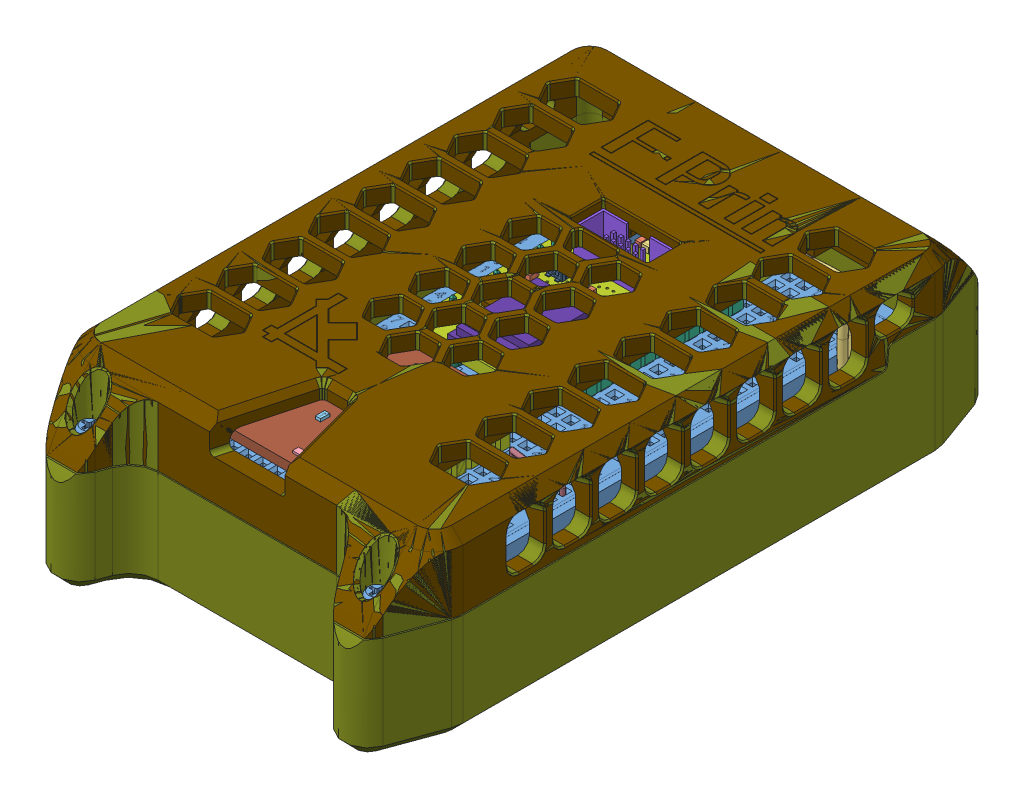
SolidWorks assembly FPR12096, configuration Screw Boss. Lengths in mm.
Overall size (66.81 31.19 108.52).
130 component instances, 41 part files, 64 mates.
Components (placement in the parent):
- HalfBreadboard.step-1: HalfBreadboard.step [Default] at (41.91 0 0)
- Thermo_28_click_v101.step-1: Thermo_28_click_v101.step [Default] at (11.403 8.3902 13.97) x (-1 0 0) z (0 1 0) size (25.78 28.57 12.19)
  - R5.step-1: R5.step [Default] at origin size (1 0.5 0.35)
    - User_Library-R_0402.step-1: User_Library-R_0402.step [Default] at (7.874 2.6926 0) x (1 0 0) z (0 0 1) size (1 0.5 0.35)
  - JP1.step-1: JP1.step [Default] at origin size (1.25 2 0.5)
    - User_Library-R_0805.step-1: User_Library-R_0805.step [Default] at (11.4299 6.5947 0) x (0 1 0) z (0 0 1) size (2 1.25 0.5)
  - U1.step-1: U1.step [Default] at origin size (1.52 1.04 0.61)
    - AS6221-AWLT-S_AMS.step-1: AS6221-AWLT-S_AMS.step [Default] at (11.4555 22.8569 0) x (1 0 0) z (0 0 1) size (1.52 1.04 0.61)
  - R3.step-1: R3.step [Default] at origin size (0.9 1.6 0.5)
    - User_Library-R_0603.step-1: User_Library-R_0603.step [Default] at (15.1129 15.2401 0) x (0 1 0) z (0 0 1) size (1.6 0.9 0.5)
  - R2.step-1: R2.step [Default] at origin size (0.9 1.6 0.5)
    - User_Library-R_0603.step-1: User_Library-R_0603.step [Default] at (11.4299 15.2147 0) x (0 1 0) z (0 0 1) size (1.6 0.9 0.5)
  - R4.step-1: R4.step [Default] at origin size (0.9 1.6 0.5)
    - User_Library-R_0603.step-1: User_Library-R_0603.step [Default] at (7.7977 15.2401 0) x (0 1 0) z (0 0 1) size (1.6 0.9 0.5)
  - C1.step-1: C1.step [Default] at origin size (0.5 1 0.5)
    - User_Library-SMD_CAPACITOR0402.step-1: User_Library-SMD_CAPACITOR0402.step [Default] at (9.9061 22.7838 0.24) x (0 -1 0) z (0 0 1) size (1 0.5 0.5)
  - MBD1.step-1: MBD1.step [Default] at origin size (25.78 20.32 12.19)
    - Header_1x8.step-1: Header_1x8.step [Default] at (-74.8548 -67.056 0) size (2.92 20.32 12.19)
      - PCB.step-1: PCB.step [Default] at origin size (2.92 20.32 12.19)
        - Free-Models.step-1: Free-Models.step [Default] at origin size (2.92 20.32 12.19)
          - 1240637040.step-1: 1240637040.step [Default] at (97.7778 84.836 -1.6002) x (0 -1 0) z (1 0 0) size (12.7 12.19 2.92)
            - User_Library-PinHeaderX5-1_PinHeaderX5_Body_1.step-1: User_Library-PinHeaderX5-1_PinHeaderX5_Body_1.step [Default] at origin size (12.7 2.54 2.92)
            - User_Library-PinHeaderX5-1_PinHeaderX5_Pins_1.step-1: User_Library-PinHeaderX5-1_PinHeaderX5_Pins_1.step [Default] at origin size (10.8 12.19 0.64)
          - 1240637040.step-2: 1240637040.step [Default] at (97.7778 77.216 -1.6002) x (0 -1 0) z (1 0 0) size (12.7 12.19 2.92)
            - User_Library-PinHeaderX5-1_PinHeaderX5_Body_1.step-1: User_Library-PinHeaderX5-1_PinHeaderX5_Body_1.step [Default] at origin size (12.7 2.54 2.92)
            - User_Library-PinHeaderX5-1_PinHeaderX5_Pins_1.step-1: User_Library-PinHeaderX5-1_PinHeaderX5_Pins_1.step [Default] at origin size (10.8 12.19 0.64)
    - Header_1x8.step-2: Header_1x8.step [Default] at (-97.7148 -67.056 0) size (2.92 20.32 12.19)
      - PCB.step-1: PCB.step [Default] at origin size (2.92 20.32 12.19)
        - Free-Models.step-1: Free-Models.step [Default] at origin size (2.92 20.32 12.19)
          - 1240637040.step-1: 1240637040.step [Default] at (97.7778 84.836 -1.6002) x (0 -1 0) z (1 0 0) size (12.7 12.19 2.92)
            - User_Library-PinHeaderX5-1_PinHeaderX5_Body_1.step-1: User_Library-PinHeaderX5-1_PinHeaderX5_Body_1.step [Default] at origin size (12.7 2.54 2.92)
            - User_Library-PinHeaderX5-1_PinHeaderX5_Pins_1.step-1: User_Library-PinHeaderX5-1_PinHeaderX5_Pins_1.step [Default] at origin size (10.8 12.19 0.64)
          - 1240637040.step-2: 1240637040.step [Default] at (97.7778 77.216 -1.6002) x (0 -1 0) z (1 0 0) size (12.7 12.19 2.92)
            - User_Library-PinHeaderX5-1_PinHeaderX5_Body_1.step-1: User_Library-PinHeaderX5-1_PinHeaderX5_Body_1.step [Default] at origin size (12.7 2.54 2.92)
            - User_Library-PinHeaderX5-1_PinHeaderX5_Pins_1.step-1: User_Library-PinHeaderX5-1_PinHeaderX5_Pins_1.step [Default] at origin size (10.8 12.19 0.64)
  - LD1.step-1: LD1.step [Default] at origin size (2.02 1.25 1.1)
    - led_0805_green.step-1: led_0805_green.step [Default] at (13.7413 1.651 0) x (-1 0 0) z (0 0 1) size (2.02 1.25 1.1)
  - R1.step-1: R1.step [Default] at origin size (2 1.25 0.5)
    - User_Library-R_0805.step-1: User_Library-R_0805.step [Default] at (13.7414 0.0001 0) x (1 0 0) z (0 0 1) size (2 1.25 0.5)
  - C2.step-1: C2.step [Default] at origin size (1 0.5 0.5)
    - User_Library-SMD_CAPACITOR0402.step-1: User_Library-SMD_CAPACITOR0402.step [Default] at (10.4139 2.6925 0.24) x (1 0 0) z (0 0 1) size (1 0.5 0.5)
  - U2.step-1: U2.step [Default] at origin size (2.76 3 1)
    - 756579480.step-1: 756579480.step [Default] at (9.144 0.7366 0) size (2.76 3 1)
      - Extruded.step-1: Extruded.step [Default] at origin size (2.76 3 1)
  - Board.step-1: Board.step [Default] at origin size (25.4 28.57 1.59)
- VCC^FPR12096-1: VCC^FPR12096 [Default] at origin (virtual)
- GND^FPR12096-1: GND^FPR12096 [Default] at origin (virtual)
- SDA^FPR12096-1: SDA^FPR12096 [Default] at origin (virtual)
- SCL^FPR12096-1: SCL^FPR12096 [Default] at origin (virtual)
- FPR12097-1: FPR12097 [Screw Boss] at (0 -6.8 0) size (66.81 30.8 108.52)
- 95495K18-1: 95495K18 [Default] at (-20 -15.1437 -33.5) x (0.277584 0 -0.960701) z (-0.960701 0 -0.277584)
- 95495K18-2: 95495K18 [Default] at (20 -15.1437 -33.5) x (0.091561 0 -0.995799) z (-0.995799 0 -0.091561)
- 95495K18-4: 95495K18 [Default] at (20 -15.1437 33.5) x (-0.125259 0 -0.992124) z (-0.992124 0 0.125259)
- 95495K18-6: 95495K18 [Default] at (-20 -15.1437 33.5) x (-0.354354 0 -0.935112) z (-0.935112 0 0.354354)
- FPR12098-1: FPR12098 [Screw Boss] at (0 -6.8 0) size (66.81 15.35 104.67)
- 99461A916-1: 99461A916 [Default] at (-25 4.955 48.5) x (1 0 0) z (0 1 0)
- 99461A916-2: 99461A916 [Default] at (25 4.955 48.5) x (1 0 0) z (0 1 0)
- 99461A916-3: 99461A916 [Default] at (-25 7.455 -48.5) x (1 0 0) z (0 1 0)
- 99461A916-4: 99461A916 [Default] at (25 7.455 -48.5) x (1 0 0) z (0 1 0)
- 2011 2000mAh Battery.step-1: 2011 2000mAh Battery.step [Default] at (0 -13.3 5) x (1 0 0) z (0 1 0)
- BatteryCable^FPR12096-1: BatteryCable^FPR12096 [Default] at origin size (51.69 24.18 9.65) (virtual)
- PHR-2-for-Battery-Adafruit.stp-1: PHR-2-for-Battery-Adafruit.stp [Default] at (11.079 8.7636 -30.135) x (0 0 1) z (-1 0 0) size (5.8 4.5 11.15)
- 5862K141-1: 5862K141 [Default] at (0 -14.5563 -15) x (1 0 0) z (0 1 0)
- 5862K141-2: 5862K141 [Default] at (0 -14.5563 15) x (0.982082 0 -0.188455) z (0 1 0)
- nRF52840 Feather-1: nRF52840 Feather [Default] at (-10.25 7.0486 -43.18) x (0 0 1) z (0 1 0) size (51.45 22.86 16.48)
  - Pin Header 1x1 TH Pitch 2.54mm^nRF52840 Feather-1: Pin Header 1x1 TH Pitch 2.54mm^nRF52840 Feather [Default] at (6.35 1.27 0.0014) x (0 1 0) z (0 0 -1) size (2.54 2.54 12.7) (virtual)
  - Pin Header 1x1 TH Pitch 2.54mm^nRF52840 Feather-56: Pin Header 1x1 TH Pitch 2.54mm^nRF52840 Feather [Default] at (8.89 1.27 0.0014) x (0 1 0) z (0 0 -1) size (2.54 2.54 12.7) (virtual)
  - Pin Header 1x1 TH Pitch 2.54mm^nRF52840 Feather-57: Pin Header 1x1 TH Pitch 2.54mm^nRF52840 Feather [Default] at (11.43 1.27 0.0014) x (0 1 0) z (0 0 -1) size (2.54 2.54 12.7) (virtual)
  - Pin Header 1x1 TH Pitch 2.54mm^nRF52840 Feather-58: Pin Header 1x1 TH Pitch 2.54mm^nRF52840 Feather [Default] at (13.97 1.27 0.0014) x (0 1 0) z (0 0 -1) size (2.54 2.54 12.7) (virtual)
  - Pin Header 1x1 TH Pitch 2.54mm^nRF52840 Feather-59: Pin Header 1x1 TH Pitch 2.54mm^nRF52840 Feather [Default] at (16.51 1.27 0.0014) x (0 1 0) z (0 0 -1) size (2.54 2.54 12.7) (virtual)
  - Pin Header 1x1 TH Pitch 2.54mm^nRF52840 Feather-60: Pin Header 1x1 TH Pitch 2.54mm^nRF52840 Feather [Default] at (19.05 1.27 0.0014) x (0 1 0) z (0 0 -1) size (2.54 2.54 12.7) (virtual)
  - Pin Header 1x1 TH Pitch 2.54mm^nRF52840 Feather-61: Pin Header 1x1 TH Pitch 2.54mm^nRF52840 Feather [Default] at (21.59 1.27 0.0014) x (0 1 0) z (0 0 -1) size (2.54 2.54 12.7) (virtual)
  - Pin Header 1x1 TH Pitch 2.54mm^nRF52840 Feather-62: Pin Header 1x1 TH Pitch 2.54mm^nRF52840 Feather [Default] at (24.13 1.27 0.0014) x (0 1 0) z (0 0 -1) size (2.54 2.54 12.7) (virtual)
  - Pin Header 1x1 TH Pitch 2.54mm^nRF52840 Feather-63: Pin Header 1x1 TH Pitch 2.54mm^nRF52840 Feather [Default] at (26.67 1.27 0.0014) x (0 1 0) z (0 0 -1) size (2.54 2.54 12.7) (virtual)
  - Pin Header 1x1 TH Pitch 2.54mm^nRF52840 Feather-64: Pin Header 1x1 TH Pitch 2.54mm^nRF52840 Feather [Default] at (29.21 1.27 0.0014) x (0 1 0) z (0 0 -1) size (2.54 2.54 12.7) (virtual)
  - Pin Header 1x1 TH Pitch 2.54mm^nRF52840 Feather-65: Pin Header 1x1 TH Pitch 2.54mm^nRF52840 Feather [Default] at (31.75 1.27 0.0014) x (0 1 0) z (0 0 -1) size (2.54 2.54 12.7) (virtual)
  - Pin Header 1x1 TH Pitch 2.54mm^nRF52840 Feather-66: Pin Header 1x1 TH Pitch 2.54mm^nRF52840 Feather [Default] at (34.29 1.27 0.0014) x (0 1 0) z (0 0 -1) size (2.54 2.54 12.7) (virtual)
  - Pin Header 1x1 TH Pitch 2.54mm^nRF52840 Feather-67: Pin Header 1x1 TH Pitch 2.54mm^nRF52840 Feather [Default] at (36.83 1.27 0.0014) x (0 1 0) z (0 0 -1) size (2.54 2.54 12.7) (virtual)
  - Pin Header 1x1 TH Pitch 2.54mm^nRF52840 Feather-68: Pin Header 1x1 TH Pitch 2.54mm^nRF52840 Feather [Default] at (39.37 1.27 0.0014) x (0 1 0) z (0 0 -1) size (2.54 2.54 12.7) (virtual)
  - Pin Header 1x1 TH Pitch 2.54mm^nRF52840 Feather-69: Pin Header 1x1 TH Pitch 2.54mm^nRF52840 Feather [Default] at (41.91 1.27 0.0014) x (0 1 0) z (0 0 -1) size (2.54 2.54 12.7) (virtual)
  - Pin Header 1x1 TH Pitch 2.54mm^nRF52840 Feather-70: Pin Header 1x1 TH Pitch 2.54mm^nRF52840 Feather [Default] at (44.45 1.27 0.0014) x (0 1 0) z (0 0 -1) size (2.54 2.54 12.7) (virtual)
  - Pin Header 1x1 TH Pitch 2.54mm^nRF52840 Feather-71: Pin Header 1x1 TH Pitch 2.54mm^nRF52840 Feather [Default] at (44.45 21.59 0.0014) x (0 -1 0) z (0 0 -1) size (2.54 2.54 12.7) (virtual)
  - Pin Header 1x1 TH Pitch 2.54mm^nRF52840 Feather-72: Pin Header 1x1 TH Pitch 2.54mm^nRF52840 Feather [Default] at (41.91 21.59 0.0014) x (0 -1 0) z (0 0 -1) size (2.54 2.54 12.7) (virtual)
  - Pin Header 1x1 TH Pitch 2.54mm^nRF52840 Feather-73: Pin Header 1x1 TH Pitch 2.54mm^nRF52840 Feather [Default] at (39.37 21.59 0.0014) x (0 -1 0) z (0 0 -1) size (2.54 2.54 12.7) (virtual)
  - Pin Header 1x1 TH Pitch 2.54mm^nRF52840 Feather-74: Pin Header 1x1 TH Pitch 2.54mm^nRF52840 Feather [Default] at (36.83 21.59 0.0014) x (0 -1 0) z (0 0 -1) size (2.54 2.54 12.7) (virtual)
  - Pin Header 1x1 TH Pitch 2.54mm^nRF52840 Feather-75: Pin Header 1x1 TH Pitch 2.54mm^nRF52840 Feather [Default] at (34.29 21.59 0.0014) x (0 -1 0) z (0 0 -1) size (2.54 2.54 12.7) (virtual)
  - Pin Header 1x1 TH Pitch 2.54mm^nRF52840 Feather-76: Pin Header 1x1 TH Pitch 2.54mm^nRF52840 Feather [Default] at (31.75 21.59 0.0014) x (0 -1 0) z (0 0 -1) size (2.54 2.54 12.7) (virtual)
  - Pin Header 1x1 TH Pitch 2.54mm^nRF52840 Feather-77: Pin Header 1x1 TH Pitch 2.54mm^nRF52840 Feather [Default] at (29.21 21.59 0.0014) x (0 -1 0) z (0 0 -1) size (2.54 2.54 12.7) (virtual)
  - Pin Header 1x1 TH Pitch 2.54mm^nRF52840 Feather-78: Pin Header 1x1 TH Pitch 2.54mm^nRF52840 Feather [Default] at (26.67 21.59 0.0014) x (0 -1 0) z (0 0 -1) size (2.54 2.54 12.7) (virtual)
  - Pin Header 1x1 TH Pitch 2.54mm^nRF52840 Feather-79: Pin Header 1x1 TH Pitch 2.54mm^nRF52840 Feather [Default] at (24.13 21.59 0.0014) x (0 -1 0) z (0 0 -1) size (2.54 2.54 12.7) (virtual)
  - Pin Header 1x1 TH Pitch 2.54mm^nRF52840 Feather-80: Pin Header 1x1 TH Pitch 2.54mm^nRF52840 Feather [Default] at (21.59 21.59 0.0014) x (0 -1 0) z (0 0 -1) size (2.54 2.54 12.7) (virtual)
  - Pin Header 1x1 TH Pitch 2.54mm^nRF52840 Feather-81: Pin Header 1x1 TH Pitch 2.54mm^nRF52840 Feather [Default] at (19.05 21.59 0.0014) x (0 -1 0) z (0 0 -1) size (2.54 2.54 12.7) (virtual)
  - Pin Header 1x1 TH Pitch 2.54mm^nRF52840 Feather-82: Pin Header 1x1 TH Pitch 2.54mm^nRF52840 Feather [Default] at (16.51 21.59 0.0014) x (0 -1 0) z (0 0 -1) size (2.54 2.54 12.7) (virtual)
  - 4062-nRF52830-Feather^nRF52840 Feather-1: 4062-nRF52830-Feather^nRF52840 Feather [Default] at origin size (51.45 22.86 6.99) (virtual)
    - PCB Component^4062-nRF52830-Feather_nRF52840 Feather-1: PCB Component^4062-nRF52830-Feather_nRF52840 Feather [Default] at origin size (51.45 22.86 6.99) (virtual)
      - Board^PCB Component_4062-nRF52830-Feather_nRF52840 Feather-1: Board^PCB Component_4062-nRF52830-Feather_nRF52840 Feather [Default] at origin size (50.8 22.86 1.99) (virtual)
      - 2x5 0.05_^PCB Component_4062-nRF52830-Feather_nRF52840 Feather-1: 2x5 0.05_^PCB Component_4062-nRF52830-Feather_nRF52840 Feather [Default] at (24.663 11.43 1.99) x (0 -1 0) z (0 0 1) size (12.8 5.2 5) (virtual)
      - 32.768^PCB Component_4062-nRF52830-Feather_nRF52840 Feather-1: 32.768^PCB Component_4062-nRF52830-Feather_nRF52840 Feather [Default] at (29.4 17.272 1.99) size (3.5 1.5 0.8) (virtual)
      - KMR2^PCB Component_4062-nRF52830-Feather_nRF52840 Feather-1: KMR2^PCB Component_4062-nRF52830-Feather_nRF52840 Feather [Default] at (11.1 6.223 1.99) size (4.6 2.8 1.94) (virtual)
      - KMR2^PCB Component_4062-nRF52830-Feather_nRF52840 Feather-2: KMR2^PCB Component_4062-nRF52830-Feather_nRF52840 Feather [Default] at (29.934 6.172 1.99) size (4.6 2.8 1.94) (virtual)
      - AP2112(3.3V)^PCB Component_4062-nRF52830-Feather_nRF52840 Feather-1: AP2112(3.3V)^PCB Component_4062-nRF52830-Feather_nRF52840 Feather [Default] at (15.138 9.144 1.99) x (-1 0 0) z (0 0 1) size (3 3 1.4) (virtual)
      - AP2112(3.3V)^PCB Component_4062-nRF52830-Feather_nRF52840 Feather-2: AP2112(3.3V)^PCB Component_4062-nRF52830-Feather_nRF52840 Feather [Default] at (18.974 13.386 1.99) x (-1 0 0) z (0 0 1) size (3 3 1.4) (virtual)
      - BLUE^PCB Component_4062-nRF52830-Feather_nRF52840 Feather-1: BLUE^PCB Component_4062-nRF52830-Feather_nRF52840 Feather [Default] at (2.083 5.639 1.99) x (0 -1 0) z (0 0 1) size (1.25 2.02 1.1) (virtual)
      - BLUE^PCB Component_4062-nRF52830-Feather_nRF52840 Feather-2: BLUE^PCB Component_4062-nRF52830-Feather_nRF52840 Feather [Default] at (2.54 17.272 1.99) x (0 1 0) z (0 0 1) size (1.25 2.02 1.1) (virtual)
      - BLUE^PCB Component_4062-nRF52830-Feather_nRF52840 Feather-3: BLUE^PCB Component_4062-nRF52830-Feather_nRF52840 Feather [Default] at (44.006 18.352 1.99) x (0 1 0) z (0 0 1) size (1.25 2.02 1.1) (virtual)
      - JSTPH^PCB Component_4062-nRF52830-Feather_nRF52840 Feather-1: JSTPH^PCB Component_4062-nRF52830-Feather_nRF52840 Feather [Default] at (10.795 19.304 1.99) size (7.9 8.6 4.8) (virtual)
      - 4u20329^PCB Component_4062-nRF52830-Feather_nRF52840 Feather-1: 4u20329^PCB Component_4062-nRF52830-Feather_nRF52840 Feather [Default] at (4.445 11.43 1.99) x (0 -1 0) z (0 0 1) size (8.8 5.6 3) (virtual)
      - MBR120^PCB Component_4062-nRF52830-Feather_nRF52840 Feather-1: MBR120^PCB Component_4062-nRF52830-Feather_nRF52840 Feather [Default] at (10.262 12.395 1.99) x (-1 0 0) z (0 0 1) size (3.6 1.4 1.35) (virtual)
      - DMG2305^PCB Component_4062-nRF52830-Feather_nRF52840 Feather-1: DMG2305^PCB Component_4062-nRF52830-Feather_nRF52840 Feather [Default] at (9.817 9.55 1.99) size (3.04 2.64 1.12) (virtual)
      - MDBT50^PCB Component_4062-nRF52830-Feather_nRF52840 Feather-1: MDBT50^PCB Component_4062-nRF52830-Feather_nRF52840 Feather [Default] at (42.545 11.43 1.99) x (0 -1 0) z (0 0 1) size (10.5 15.5 2.05) (virtual)
      - GD25Q16^PCB Component_4062-nRF52830-Feather_nRF52840 Feather-1: GD25Q16^PCB Component_4062-nRF52830-Feather_nRF52840 Feather [Default] at (40.767 4.953 1.99) x (-1 0 0) z (0 0 1) size (3 2 0.8) (virtual)
      - WS2812B3535^PCB Component_4062-nRF52830-Feather_nRF52840 Feather-1: WS2812B3535^PCB Component_4062-nRF52830-Feather_nRF52840 Feather [Default] at (19.387 6.145 1.99) x (-1 0 0) z (0 0 1) size (3.5 3.5 1.2) (virtual)
      - 0.1uF^PCB Component_4062-nRF52830-Feather_nRF52840 Feather-1: 0.1uF^PCB Component_4062-nRF52830-Feather_nRF52840 Feather [Default] at (19.075 8.788 1.99) size (1.6 0.9 0.8) (virtual)
      - 0.1uF^PCB Component_4062-nRF52830-Feather_nRF52840 Feather-2: 0.1uF^PCB Component_4062-nRF52830-Feather_nRF52840 Feather [Default] at (29.312 18.936 1.99) x (-1 0 0) z (0 0 1) size (1.6 0.9 0.8) (virtual)
      - 0.1uF^PCB Component_4062-nRF52830-Feather_nRF52840 Feather-3: 0.1uF^PCB Component_4062-nRF52830-Feather_nRF52840 Feather [Default] at (26.264 18.974 1.99) x (-1 0 0) z (0 0 1) size (1.6 0.9 0.8) (virtual)
      - 0.1uF^PCB Component_4062-nRF52830-Feather_nRF52840 Feather-4: 0.1uF^PCB Component_4062-nRF52830-Feather_nRF52840 Feather [Default] at (31.394 11.9 1.99) size (1.6 0.9 0.8) (virtual)
      - 0.1uF^PCB Component_4062-nRF52830-Feather_nRF52840 Feather-5: 0.1uF^PCB Component_4062-nRF52830-Feather_nRF52840 Feather [Default] at (5.69 20.053 1.99) x (0 -1 0) z (0 0 1) size (1.6 0.9 0.8) (virtual)
      - 0.1uF^PCB Component_4062-nRF52830-Feather_nRF52840 Feather-6: 0.1uF^PCB Component_4062-nRF52830-Feather_nRF52840 Feather [Default] at (40.678 18.339 1.99) x (-1 0 0) z (0 0 1) size (1.6 0.9 0.8) (virtual)
      - 0.1uF^PCB Component_4062-nRF52830-Feather_nRF52840 Feather-7: 0.1uF^PCB Component_4062-nRF52830-Feather_nRF52840 Feather [Default] at (6.756 7.379 1.99) x (0 1 0) z (0 0 1) size (1.6 0.9 0.8) (virtual)
      - 0.1uF^PCB Component_4062-nRF52830-Feather_nRF52840 Feather-8: 0.1uF^PCB Component_4062-nRF52830-Feather_nRF52840 Feather [Default] at (15.316 5.309 1.99) size (1.6 0.9 0.8) (virtual)
      - 0.1uF^PCB Component_4062-nRF52830-Feather_nRF52840 Feather-9: 0.1uF^PCB Component_4062-nRF52830-Feather_nRF52840 Feather [Default] at (33.655 4.191 1.99) size (1.6 0.9 0.8) (virtual)
      - 0.1uF^PCB Component_4062-nRF52830-Feather_nRF52840 Feather-10: 0.1uF^PCB Component_4062-nRF52830-Feather_nRF52840 Feather [Default] at (36.766 5.27 1.99) size (1.6 0.9 0.8) (virtual)
      - 0.1uF^PCB Component_4062-nRF52830-Feather_nRF52840 Feather-11: 0.1uF^PCB Component_4062-nRF52830-Feather_nRF52840 Feather [Default] at (32.322 17.78 1.99) x (0 1 0) z (0 0 1) size (1.6 0.9 0.8) (virtual)
      - 10uF^PCB Component_4062-nRF52830-Feather_nRF52840 Feather-1: 10uF^PCB Component_4062-nRF52830-Feather_nRF52840 Feather [Default] at (19.05 10.249 1.99) size (2 1.25 1) (virtual)
      - 10uF^PCB Component_4062-nRF52830-Feather_nRF52840 Feather-2: 10uF^PCB Component_4062-nRF52830-Feather_nRF52840 Feather [Default] at (20.892 17.272 1.99) x (0 1 0) z (0 0 1) size (2 1.25 1) (virtual)
      - 10uF^PCB Component_4062-nRF52830-Feather_nRF52840 Feather-3: 10uF^PCB Component_4062-nRF52830-Feather_nRF52840 Feather [Default] at (12.294 9.855 1.99) x (0 1 0) z (0 0 1) size (2 1.25 1) (virtual)
      - 10uF^PCB Component_4062-nRF52830-Feather_nRF52840 Feather-4: 10uF^PCB Component_4062-nRF52830-Feather_nRF52840 Feather [Default] at (31.242 10.274 1.99) size (2 1.25 1) (virtual)
      - 10uF^PCB Component_4062-nRF52830-Feather_nRF52840 Feather-5: 10uF^PCB Component_4062-nRF52830-Feather_nRF52840 Feather [Default] at (15.316 12.256 1.99) x (-1 0 0) z (0 0 1) size (2 1.25 1) (virtual)
      - DNP^PCB Component_4062-nRF52830-Feather_nRF52840 Feather-1: DNP^PCB Component_4062-nRF52830-Feather_nRF52840 Feather [Default] at (33.82 9.436 1.99) x (0 -1 0) z (0 0 1) size (2 1.25 0.85) (virtual)
      - 100K^PCB Component_4062-nRF52830-Feather_nRF52840 Feather-1: 100K^PCB Component_4062-nRF52830-Feather_nRF52840 Feather [Default] at (17.374 17.501 1.99) x (-1 0 0) z (0 0 1) size (3.05 1.6 0.5) (virtual)
Mates (geometry in assembly coordinates):
- Coincident1: coincident aligned: plane of HalfBreadboard.step-1 through (41.91 0 0) normal (0 0 1)
- Coincident2: coincident aligned: plane of HalfBreadboard.step-1 through (41.91 0 0) normal (0 1 0)
- Symmetric1: symmetric aligned: plane of HalfBreadboard.step-1 through (27.375 4.25 40.84) normal (1 0 0); plane of HalfBreadboard.step-1 through (-27.375 4.25 40.84) normal (-1 0 0)
- Distance1: distance = 1.27 mm anti-aligned: plane of Nano33BLE-1 through (1.27 7.05 -40.59) normal (-1 0 0)
- Coincident4: coincident anti-aligned: plane of HalfBreadboard.step-1 through (0 4.25 -41.91) normal (0 1 0); plane of Nano33BLE-1/Pin Header 1x15 TH Pitch 2.54mm.stp-1 through (10.1854 4.25 -37.723) normal (0 -1 0)
- Distance2: distance = 0.25 mm aligned: plane of Nano33BLE-1/Nano33BLE.step-1/NANO33BLE_V2.0 v1.step-1/Board (1).step-1 through (10.16 7.05 -40.59) normal (0 0 -1); plane of HalfBreadboard.step-1 through (-27.375 -5.25 -40.84) normal (0 0 -1)
- Coincident10: coincident anti-aligned: plane of HalfBreadboard.step-1 through (0 4.25 -41.91) normal (0 1 0); plane of Thermo_28_click_v101.step-1/MBD1.step-1/Header_1x8.step-2/PCB.step-1/Free-Models.step-1/1240637040.step-1/User_Library-PinHeaderX5-1_PinHeaderX5_Body_1.step-1 through (11.34 4.25 31.75) normal (0 -1 0)
- Width1: width aligned: plane of Thermo_28_click_v101.step-1/MBD1.step-1/Header_1x8.step-1/PCB.step-1/Free-Models.step-1/1240637040.step-2/User_Library-PinHeaderX5-1_PinHeaderX5_Body_1.step-1 through (-12.98 6.79 13.97) normal (-1 0 0); plane of Thermo_28_click_v101.step-1/MBD1.step-1/Header_1x8.step-1/PCB.step-1/Free-Models.step-1/1240637040.step-2/User_Library-PinHeaderX5-1_PinHeaderX5_Body_1.step-1 through (-10.06 6.79 13.97) normal (1 0 0); plane of HalfBreadboard.step-1 through (-11.17 -2.75 6.7) normal (-1 0 0); plane of HalfBreadboard.step-1 through (-11.87 -2.75 6.7) normal (1 0 0)
- Width2: width anti-aligned: plane of Thermo_28_click_v101.step-1/MBD1.step-1/Header_1x8.step-1/PCB.step-1/Free-Models.step-1/1240637040.step-2/User_Library-PinHeaderX5-1_PinHeaderX5_Body_1.step-1 through (-11.52 6.79 12.7) normal (0 0 -1); plane of Thermo_28_click_v101.step-1/MBD1.step-1/Header_1x8.step-1/PCB.step-1/Free-Models.step-1/1240637040.step-1/User_Library-PinHeaderX5-1_PinHeaderX5_Body_1.step-1 through (-11.52 6.79 33.02) normal (0 0 1); plane of HalfBreadboard.step-1 through (-13.71 -2.75 13.62) normal (0 0 1); plane of HalfBreadboard.step-1 through (-13.71 -2.75 32.1) normal (0 0 -1)
- Coincident12: coincident anti-aligned: plane of HalfBreadboard.step-1 through (0 -5.25 -41.91) normal (0 -1 0); plane of FPR12097-1 through (0 -5.25 0) normal (0 1 0)
- Coincident13: coincident aligned: plane of FPR12097-1 through (0 -6.8 0) normal (1 0 0)
- Coincident14: coincident aligned: plane of FPR12097-1 through (0 -6.8 0) normal (0 0 1)
- Coincident15: coincident anti-aligned: plane of FPR12097-1 through (-20 -14.35 -33.5) normal (0 -1 0); plane of 95495K18-1 through (-26.1005 -14.35 -35.2627) normal (0 1 0)
- Concentric1: concentric aligned: cone of 95495K18-1 through (-20 -15.8076 -33.5) axis (0 -1 0); circle of FPR12097-1
- Coincident16: coincident anti-aligned: plane of FPR12097-1 through (20 -14.35 -33.5) normal (0 -1 0); plane of 95495K18-2 through (13.6767 -14.35 -34.0814) normal (0 1 0)
- Concentric2: concentric aligned: cone of 95495K18-2 through (20 -15.8076 -33.5) axis (0 -1 0); circle of FPR12097-1
- Coincident17: coincident anti-aligned: plane of FPR12097-1 through (20 -14.35 33.5) normal (0 -1 0); plane of 95495K18-4 through (13.7 -14.35 34.2954) normal (0 1 0)
- Concentric3: concentric aligned: cone of 95495K18-4 through (20 -15.8076 33.5) axis (0 -1 0); circle of FPR12097-1
- Coincident18: coincident anti-aligned: plane of FPR12097-1 through (-20 -14.35 33.5) normal (0 -1 0); plane of 95495K18-6 through (-25.938 -14.35 35.7501) normal (0 1 0)
- Concentric4: concentric aligned: cone of 95495K18-6 through (-20 -15.8076 33.5) axis (0 -1 0); circle of FPR12097-1
- Coincident21: coincident aligned: plane of FPR12097-1 through (0 -6.8 0) normal (0 0 1); plane of FPR12098-1 through (0 -6.8 0) normal (0 0 1)
- Coincident22: coincident aligned: plane of FPR12097-1 through (0 -6.8 0) normal (0 1 0); plane of FPR12098-1 through (0 -6.8 0) normal (0 1 0)
- Coincident23: coincident aligned: plane of FPR12097-1 through (0 -6.8 0) normal (1 0 0); plane of FPR12098-1 through (0 -6.8 0) normal (1 0 0)
- Concentric7: concentric anti-aligned: cylinder of 99461A916-1 through (-25 6.355 48.5) axis (0 1 0) radius 1.75; circle of FPR12098-1
- Parallel1: parallel aligned: plane of 99461A916-1 through (-25 4.955 48.5) normal (1 0 0)
- Coincident25: coincident anti-aligned: plane of 99461A916-1 through (-25 4.955 47.925) normal (0 -1 0); plane of FPR12098-1 through (-25 4.955 48.5) normal (0 1 0)
- Concentric8: concentric anti-aligned: cylinder of 99461A916-2 through (25 6.355 48.5) axis (0 1 0) radius 1.75; circle of FPR12098-1
- Parallel2: parallel aligned: plane of 99461A916-2 through (25 4.955 48.5) normal (1 0 0)
- Coincident26: coincident anti-aligned: plane of 99461A916-2 through (25 4.955 47.925) normal (0 -1 0); plane of FPR12098-1 through (25 4.955 48.5) normal (0 1 0)
- Parallel3: parallel aligned: plane of 99461A916-3 through (-25 7.455 -48.5) normal (1 0 0)
- Concentric9: concentric anti-aligned: cylinder of 99461A916-3 through (-25 8.855 -48.5) axis (0 1 0) radius 1.75; circle of FPR12098-1
- Coincident27: coincident anti-aligned: plane of 99461A916-3 through (-25 7.455 -49.075) normal (0 -1 0); plane of FPR12098-1 through (-25 7.455 -48.5) normal (0 1 0)
- Parallel4: parallel aligned: plane of 99461A916-4 through (25 7.455 -48.5) normal (1 0 0)
- Concentric10: concentric anti-aligned: cylinder of 99461A916-4 through (25 8.855 -48.5) axis (0 1 0) radius 1.75; circle of FPR12098-1
- Coincident28: coincident anti-aligned: plane of 99461A916-4 through (25 7.455 -49.075) normal (0 -1 0); plane of FPR12098-1 through (25 7.455 -48.5) normal (0 1 0)
- Coincident29: coincident anti-aligned: plane of HalfBreadboard.step-1 through (0 4.25 -41.91) normal (0 1 0); plane of nRF52840 Feather-1/Pin Header 1x1 TH Pitch 2.54mm^nRF52840 Feather-1 through (-9.923 4.25 -38.1254) normal (0 -1 0)
- Width3: width: plane of HalfBreadboard.step-1 through (-8.63 -2.75 -37.18) normal (0 0 1); plane of nRF52840 Feather-1/4062-nRF52830-Feather.step-2/Copy of nRFBoard^4062-nRF52830-Feather.step-1 through (-8.63 -2.75 -36.48) normal (0 0 -1); cylinder of HalfBreadboard.step-1 through (-8.98 7.0486 -36.83) axis (0 1 0) radius 0.5
- Width4: width: plane of HalfBreadboard.step-1 through (-9.33 -2.75 -36.48) normal (1 0 0); plane of nRF52840 Feather-1/4062-nRF52830-Feather.step-2/Copy of nRFBoard^4062-nRF52830-Feather.step-1 through (-8.63 -2.75 -36.48) normal (-1 0 0); cylinder of HalfBreadboard.step-1 through (-8.98 7.0486 -36.83) axis (0 1 0) radius 0.5
- Parallel5: parallel anti-aligned: plane of nRF52840 Feather-1 through (1.18 7.0486 -43.18) normal (-1 0 0)
- Width6: width anti-aligned: plane of PHR-2-for-Battery-Adafruit.stp-1 through (12.6648 13.8386 -30.085) normal (0 0 1); plane of nRF52840 Feather-1/4062-nRF52830-Feather^nRF52840 Feather-1/PCB Component^4062-nRF52830-Feather_nRF52840 Feather-1/JSTPH^PCB Component_4062-nRF52830-Feather_nRF52840 Feather-1 through (12.6648 13.8386 -34.685) normal (0 0 -1); plane of PHR-2-for-Battery-Adafruit.stp-1 through (12.254 9.6386 -29.435) normal (0 0 -1); plane of nRF52840 Feather-1/4062-nRF52830-Feather^nRF52840 Feather-1/PCB Component^4062-nRF52830-Feather_nRF52840 Feather-1/JSTPH^PCB Component_4062-nRF52830-Feather_nRF52840 Feather-1 through (12.254 13.2386 -35.335) normal (0 0 1)
- Coincident33: coincident anti-aligned: plane of PHR-2-for-Battery-Adafruit.stp-1 through (8.254 11.6886 -35.285) normal (-1 0 0); plane of nRF52840 Feather-1/4062-nRF52830-Feather^nRF52840 Feather-1/PCB Component^4062-nRF52830-Feather_nRF52840 Feather-1/JSTPH^PCB Component_4062-nRF52830-Feather_nRF52840 Feather-1 through (8.254 13.8386 -32.385) normal (1 0 0)
- Width7: width aligned: plane of PHR-2-for-Battery-Adafruit.stp-1 through (8.704 12.4386 -31.685) normal (0 -1 0); plane of nRF52840 Feather-1/4062-nRF52830-Feather^nRF52840 Feather-1/PCB Component^4062-nRF52830-Feather_nRF52840 Feather-1/JSTPH^PCB Component_4062-nRF52830-Feather_nRF52840 Feather-1 through (8.704 11.8386 -31.685) normal (0 1 0); plane of PHR-2-for-Battery-Adafruit.stp-1 through (12.254 11.8886 -31.635) normal (0 -1 0); plane of nRF52840 Feather-1/4062-nRF52830-Feather^nRF52840 Feather-1/PCB Component^4062-nRF52830-Feather_nRF52840 Feather-1/JSTPH^PCB Component_4062-nRF52830-Feather_nRF52840 Feather-1 through (12.254 12.3886 -31.135) normal (0 1 0)
- Coincident34: coincident aligned: plane of FPR12097-1 through (-27.5 -17.5 -41) normal (0 -1 0); plane of FPR12103-1 through (15.8 -17.5 -30.8) normal (0 -1 0)
- Width8: width anti-aligned: plane of FPR12097-1 through (20.5 75.8734 -35) normal (-1 0 0); plane of FPR12103-1 through (-20.5 75.8734 -35) normal (1 0 0); plane of FPR12097-1 through (-19.8 -17.5 -30.8) normal (-1 0 0); plane of FPR12103-1 through (19.8 -17.5 -30.8) normal (1 0 0)
- Coincident35: coincident aligned: plane of FPR12103-1 through (0 -15.75 0) normal (0 0 1)
- Parallel6: parallel aligned: plane of 99461A916-5 through (0 -15.5 -38) normal (1 0 0)
- Concentric11: concentric anti-aligned: cylinder of 99461A916-5 through (0 -16.9 -38) axis (0 -1 0) radius 1.75; cone of FPR12097-1 through (0 -12.65 -38) axis (0 1 0)
- Coincident36: coincident anti-aligned: plane of 99461A916-5 through (0 -15.5 -37.425) normal (0 1 0); plane of FPR12103-1 through (0 -15.5 -37.35) normal (0 -1 0)
- Parallel7: parallel aligned: plane of 99461A916-6 through (0 -15.5 38) normal (1 0 0)
- Concentric12: concentric anti-aligned: cylinder of 99461A916-6 through (0 -16.9 38) axis (0 -1 0) radius 1.75; cone of FPR12097-1 through (0 -12.65 38) axis (0 1 0)
- Coincident37: coincident anti-aligned: plane of 99461A916-6 through (0 -15.5 38.575) normal (0 1 0); plane of FPR12103-1 through (0 -15.5 37.35) normal (0 -1 0)
- Concentric13: concentric aligned: cone of FPR12103-1 through (0 -17.4 -15) axis (0 -1 0); cylinder of 5862K141-1 through (0 -13.7625 -15) axis (0 -1 0) radius 3.175
- Coincident38: coincident anti-aligned: plane of FPR12103-1 through (15.8 -17.4 -30.8) normal (0 1 0); plane of 5862K141-1 through (0 -15.35 -15) normal (0 -1 0)
- Concentric14: concentric aligned: cone of FPR12103-1 through (0 -17.4 15) axis (0 -1 0); cylinder of 5862K141-2 through (0 -13.7625 15) axis (0 -1 0) radius 3.175
- Coincident39: coincident anti-aligned: plane of FPR12103-1 through (15.8 -17.4 -30.8) normal (0 1 0); plane of 5862K141-2 through (0 -15.35 15) normal (0 -1 0)
- Coincident40: coincident anti-aligned: plane of FPR12097-1 through (-27.5 -15.35 -41) normal (0 1 0); plane of 5862K141-1 through (0 -15.35 -15) normal (0 -1 0)
- Concentric15: concentric aligned: circle of FPR12097-1; cylinder of 5862K141-1 through (0 -13.7625 -15) axis (0 -1 0) radius 3.175
- Concentric16: concentric anti-aligned: circle of FPR12097-1; cylinder of 5862K141-2 through (0 -13.7625 15) axis (0 -1 0) radius 3.175
- Coincident41: coincident anti-aligned: plane of FPR12097-1 through (-27.5 -15.35 -41) normal (0 1 0); plane of 5862K141-2 through (0 -15.35 15) normal (0 -1 0)
- Coincident42: coincident aligned: plane of 2011 2000mAh Battery.step-1 through (0 -13.3 5) normal (1 0 0)
- Coincident43: coincident anti-aligned: plane of FPR12097-1 through (-27.5 -13.3 -41) normal (0 1 0); plane of 2011 2000mAh Battery.step-1 through (0 -13.3 5) normal (0 -1 0)
- Coincident44: coincident anti-aligned: plane of FPR12097-1 through (-20 -104.0193 35) normal (0 0 -1); plane of 2011 2000mAh Battery.step-1 through (-18.5 -13.3 35) normal (0 0 1)
- Width9: width: plane of HalfBreadboard.step-1 through (-8.63 -2.75 -36.48) normal (0 0 -1); plane of nRF52840 Feather-1/4062-nRF52830-Feather^nRF52840 Feather-1/PCB Component^4062-nRF52830-Feather_nRF52840 Feather-1/Board^PCB Component_4062-nRF52830-Feather_nRF52840 Feather-1 through (-8.63 -2.75 -37.18) normal (0 0 1); cylinder of HalfBreadboard.step-1 through (-8.98 7.0486 -36.83) axis (0 1 0) radius 0.5
- Width10: width: plane of HalfBreadboard.step-1 through (-8.63 -2.75 -36.48) normal (-1 0 0); plane of nRF52840 Feather-1/4062-nRF52830-Feather^nRF52840 Feather-1/PCB Component^4062-nRF52830-Feather_nRF52840 Feather-1/Board^PCB Component_4062-nRF52830-Feather_nRF52840 Feather-1 through (-9.33 -2.75 -36.48) normal (1 0 0); cylinder of HalfBreadboard.step-1 through (-8.98 7.0486 -36.83) axis (0 1 0) radius 0.5
